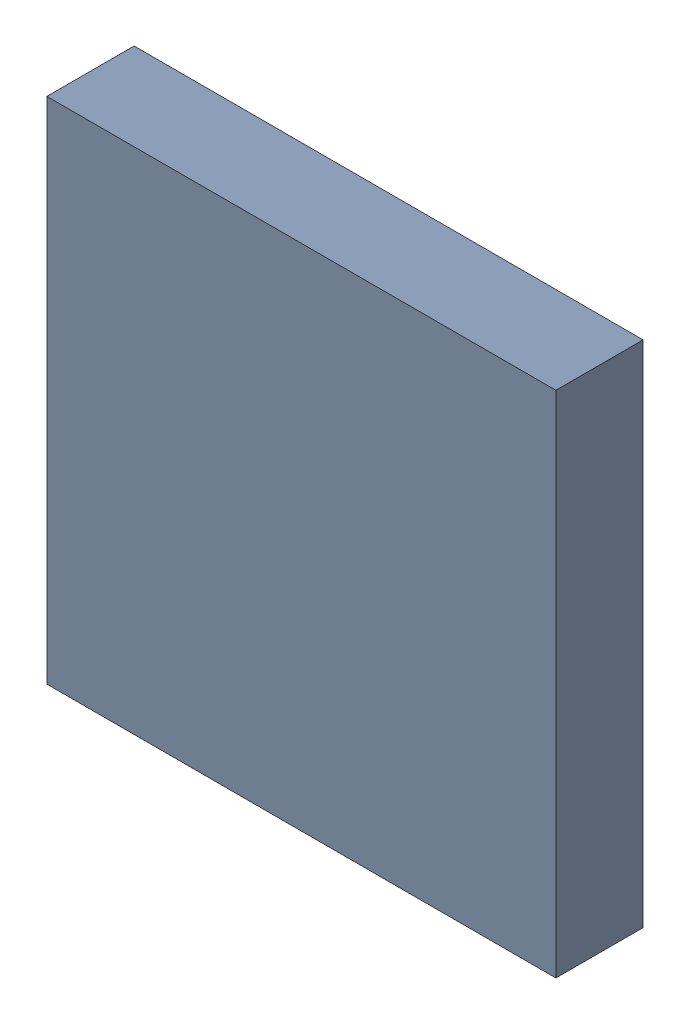
SolidWorks assembly U4-1, configuration Default. Lengths in mm.
Overall size (7 7 1.2).
2 component instances, 1 part files, 0 mates.
Components (placement in the parent):
- 959209752-1-1: 959209752-1 [Default] at (110.9632 83.702 0) size (7 7 1.2)
  - Extruded-59-1: Extruded-59 [Default] at origin size (7 7 1.2)
